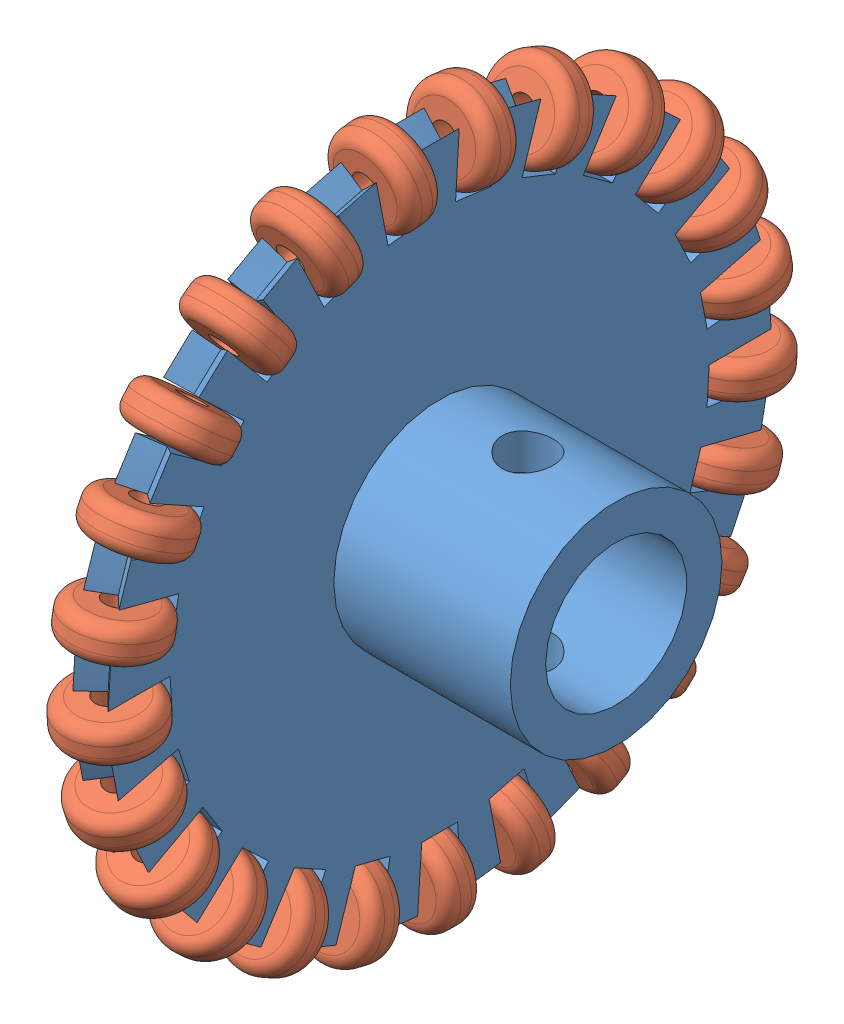
SolidWorks assembly Follower_wheel, configuration Default. Lengths in mm.
Overall size (14.36 42.16 42.24).
26 component instances, 2 part files, 5 mates.
Components (placement in the parent):
- Follower Wheel-1: Follower Wheel [Default] at origin size (12 37.52 37.56)
- bead-1: bead [Default] at (0 17.6007 2.2235) x (0 0.125333 -0.992115) z (0.45035 0.885812 0.111904) size (2 5 5)
- bead-2: bead [Default] at (0 16.4948 6.5307) x (0 0.368125 -0.929776) z (0.45035 0.830153 0.328681) size (2 5 5)
- bead-3: bead [Default] at (0 14.3524 10.4276) x (0 0.587785 -0.809017) z (0.45035 0.722333 0.524805) size (2 5 5)
- bead-4: bead [Default] at (0 11.3083 13.6693) x (0 0.770513 -0.637424) z (0.45035 0.569125 0.687954) size (2 5 5)
- bead-5: bead [Default] at (0 7.5536 16.0521) x (0 0.904827 -0.425779) z (0.45035 0.380158 0.807877) size (2 5 5)
- bead-6: bead [Default] at (0 3.3243 17.4263) x (0 0.982287 -0.187381) z (0.45035 0.167304 0.877037) size (2 5 5)
- bead-7: bead [Default] at (0 -1.1139 17.7056) x (0 0.998027 0.062791) z (0.45035 -0.056063 0.89109) size (2 5 5)
- bead-8: bead [Default] at (0 -5.4821 16.8723) x (0 0.951057 0.309017) z (0.45035 -0.275907 0.849153) size (2 5 5)
- bead-9: bead [Default] at (0 -9.5059 14.9789) x (0 0.844328 0.535827) z (0.45035 -0.478414 0.75386) size (2 5 5)
- bead-10: bead [Default] at (0 -12.9323 12.1443) x (0 0.684547 0.728969) z (0.45035 -0.650861 0.611199) size (2 5 5)
- bead-11: bead [Default] at (0 -15.5462 8.5466) x (0 0.481754 0.876307) z (0.45035 -0.782412 0.430135) size (2 5 5)
- bead-12: bead [Default] at (0 -17.1832 4.4119) x (0 0.24869 0.968583) z (0.45035 -0.864802 0.222043) size (2 5 5)
- bead-13: bead [Default] at (0 -17.7406 0) x (0 0 1) z (0.45035 -0.892852 0) size (2 5 5)
- bead-14: bead [Default] at (0 -17.1832 -4.4119) x (0 -0.24869 0.968583) z (0.45035 -0.864802 -0.222043) size (2 5 5)
- bead-15: bead [Default] at (0 -15.5462 -8.5466) x (0 -0.481754 0.876307) z (0.45035 -0.782412 -0.430135) size (2 5 5)
- bead-16: bead [Default] at (0 -12.9323 -12.1443) x (0 -0.684547 0.728969) z (0.45035 -0.650861 -0.611199) size (2 5 5)
- bead-17: bead [Default] at (0 -9.5059 -14.9789) x (0 -0.844328 0.535827) z (0.45035 -0.478414 -0.75386) size (2 5 5)
- bead-18: bead [Default] at (0 -5.4821 -16.8723) x (0 -0.951057 0.309017) z (0.45035 -0.275907 -0.849153) size (2 5 5)
- bead-19: bead [Default] at (0 -1.1139 -17.7056) x (0 -0.998027 0.062791) z (0.45035 -0.056063 -0.89109) size (2 5 5)
- bead-20: bead [Default] at (0 3.3243 -17.4263) x (0 -0.982287 -0.187381) z (0.45035 0.167304 -0.877037) size (2 5 5)
- bead-21: bead [Default] at (0 7.5536 -16.0521) x (0 -0.904827 -0.425779) z (0.45035 0.380158 -0.807877) size (2 5 5)
- bead-22: bead [Default] at (0 11.3083 -13.6693) x (0 -0.770513 -0.637424) z (0.45035 0.569125 -0.687954) size (2 5 5)
- bead-23: bead [Default] at (0 14.3524 -10.4276) x (0 -0.587785 -0.809017) z (0.45035 0.722333 -0.524805) size (2 5 5)
- bead-24: bead [Default] at (0 16.4948 -6.5307) x (0 -0.368125 -0.929776) z (0.45035 0.830153 -0.328681) size (2 5 5)
- bead-25: bead [Default] at (0 17.6007 -2.2235) x (0 -0.125333 -0.992115) z (0.45035 0.885812 -0.111904) size (2 5 5)
Mates (geometry in assembly coordinates):
- Coincident1: coincident aligned: plane of Follower Wheel-1 through (0 0 0) normal (0 1 0)
- Coincident2: coincident aligned: plane of Follower Wheel-1 through (0 0 0) normal (1 0 0)
- Coincident3: coincident aligned: plane of Follower Wheel-1 through (0 0 0) normal (0 0 1)
- Width1: width aligned: plane of Follower Wheel-1 through (-9 0 0) normal (0 -0.05902 0.998257); plane of bead-1 through (-9 0 0) normal (0 0.191091 -0.981572); plane of Follower Wheel-1 through (0 17.726 1.2314) normal (0 0.125333 -0.992115); plane of bead-1 through (0 17.4753 3.2156) normal (0 -0.125333 0.992115)
- Concentric1: concentric aligned: cylinder of bead-1 through (0 17.726 1.2314) axis (0 -0.125333 0.992115) radius 0.75
